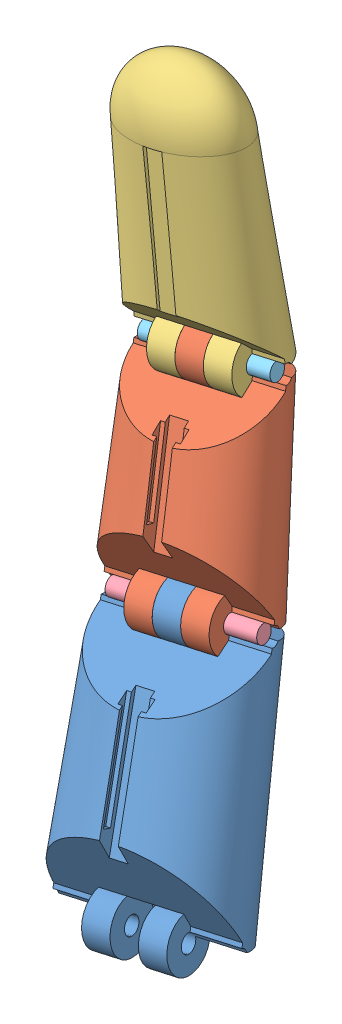
SolidWorks assembly Assem2 pinky, configuration Default. Lengths in mm.
Overall size (30.65 84.82 33.05).
5 component instances, 5 part files, 8 mates.
Components (placement in the parent):
- part 1 pinky-1: part 1 pinky [Default] at (-1.3014 53.9301 11.8427) x (-0.983786 -0.113216 0.139093) z (0.091703 0.34896 0.93264) size (20.08 34 15.01)
- part 2 pinky-1: part 2 pinky [Default] at (-4.6872 75.8419 5.7312) x (-0.983786 -0.113216 0.139093) z (0.102667 0.280394 0.954379) size (18.07 29 13.01)
- part 3 pinky-1: part 3 pinky [Default] at (-7.2345 98.6713 6.2965) x (-0.983786 -0.113216 0.139093) z (0.141692 -0.015201 0.989794) size (16.07 32.5 11.01)
- mate11-1: mate11 [Default] at (6.4918 55.301 10.5635) x (0.167431 -0.301812 0.93855) z (-0.983786 -0.113216 0.139093) size (2 2 16)
- mate22-1: mate22 [Default] at (2.1258 77.111 4.6254) x (0.15822 -0.913063 0.375874) z (-0.983786 -0.113216 0.139093) size (2 2 14)
Mates (geometry in assembly coordinates):
- Concentric2: concentric aligned: cylinder of part 1 pinky-1 through (8.4698 55.5287 10.2838) axis (-0.983786 -0.113216 0.139093) radius 1; cylinder of part 2 pinky-1 through (7.4849 55.4153 10.4231) axis (-0.983786 -0.113216 0.139093) radius 1
- Coincident1: coincident anti-aligned: plane of part 1 pinky-1 through (0.0972 54.5651 11.4676) normal (0.983786 0.113216 -0.139093); plane of part 2 pinky-1 through (0.0972 54.5651 11.4676) normal (-0.983786 -0.113216 0.139093)
- Concentric3: concentric anti-aligned: cylinder of part 2 pinky-1 through (4.1027 77.3385 4.3459) axis (-0.983786 -0.113216 0.139093) radius 1; cylinder of part 3 pinky-1 through (-12.6388 75.4119 6.7129) axis (0.983786 0.113216 -0.139093) radius 1
- Coincident2: coincident anti-aligned: plane of part 2 pinky-1 through (-3.285 76.4884 5.3904) normal (0.983786 0.113216 -0.139093); plane of part 3 pinky-1 through (-3.285 76.4884 5.3904) normal (-0.983786 -0.113216 0.139093)
- Concentric4: concentric anti-aligned: cylinder of part 2 pinky-1 through (7.4849 55.4153 10.4231) axis (-0.983786 -0.113216 0.139093) radius 1; cylinder of mate11-1 through (-9.2488 53.4896 12.789) axis (0.983786 0.113216 -0.139093) radius 1
- Concentric5: concentric aligned: cylinder of part 3 pinky-1 through (-12.6388 75.4119 6.7129) axis (0.983786 0.113216 -0.139093) radius 1; cylinder of mate22-1 through (-11.6472 75.526 6.5727) axis (0.983786 0.113216 -0.139093) radius 1
- Width1: width anti-aligned: plane of mate22-1 through (2.1258 77.111 4.6254) normal (0.983786 0.113216 -0.139093); plane of part 3 pinky-1 through (-11.6472 75.526 6.5727) normal (-0.983786 -0.113216 0.139093); plane of mate22-1 through (-9.1877 75.8091 6.225) normal (-0.983786 -0.113216 0.139093); plane of part 3 pinky-1 through (-0.3336 76.828 4.9732) normal (0.983786 0.113216 -0.139093)
- Width2: width anti-aligned: plane of mate11-1 through (6.4918 55.301 10.5635) normal (0.983786 0.113216 -0.139093); plane of part 2 pinky-1 through (-9.2488 53.4896 12.789) normal (-0.983786 -0.113216 0.139093); plane of mate11-1 through (-5.8055 53.8858 12.3022) normal (-0.983786 -0.113216 0.139093); plane of part 2 pinky-1 through (3.0486 54.9048 11.0503) normal (0.983786 0.113216 -0.139093)
